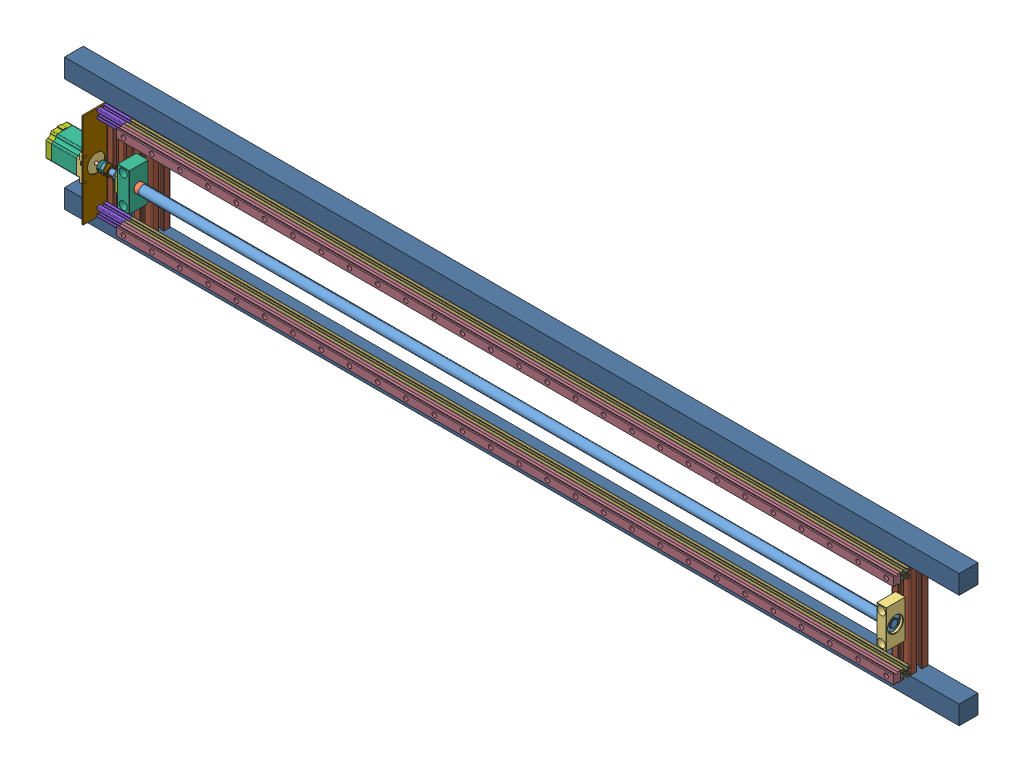
SolidWorks assembly Linke_seite, configuration Standard. Lengths in mm.
Overall size (1900 280 89.2).
42 component instances, 28 part files, 47 mates.
Components (placement in the parent):
- y.1-1: y.1 [Standard] at (-1768.993 -964.2695 1185.6748) x (-1 0 0) z (0 -0.561643 0.82738) size (1670 20 20)
- y.3-1: y.3 [Standard] at (-1768.993 -964.2695 1185.6748) x (-1 0 0) z (0 0.924225 0.381849) size (15 20 20)
- buv15_2_14b-1: buv15_2_14b [Standard] at (-1786.493 -964.2695 1185.6748) x (1 0 0) z (0 -1 0) size (20 41 80)
  - y.1.1.1-1: y.1.1.1 [Standard] at origin size (20 41 80)
  - y.2.1.1-1: y.2.1.1 [Standard] at (5 0 0) size (1 20 17.6)
  - y.3.1.1-1: y.3.1.1 [Standard] at origin size (9 32 32)
- bsv15_2_14b-1: bsv15_2_14b [Standard] at (-3373.993 -964.2695 1185.6748) x (-1 0 0) z (0 1 0) size (43 41 80)
  - y.1.1-1: y.1.1 [Standard] at origin size (25 41 80)
  - y.2.1-1: y.2.1 [Standard] at origin size (8 37 37)
  - y.3.1-1: y.3.1 [Standard] at origin size (18 32 32)
  - y.4.1-1: y.4.1 [Standard] at origin size (10 20 20)
  - y.5.1-1: y.5.1 [Standard] at origin size (10 26.45 26.45)
- bosch_3842993120_6do5v09iy6ebk03fg871s10o3-1: bosch_3842993120_6do5v09iy6ebk03fg871s10o3 [Default] at (-1776.493 -1064.2695 1144.6748) x (0 1 0) z (0 0 1) size (200 40 40)
- bosch_3842993120_6do5v09iy6ebk03fg871s10o3-2: bosch_3842993120_6do5v09iy6ebk03fg871s10o3 [Default] at (-3386.493 -1064.2695 1144.6748) x (0 1 0) z (0 0 1) size (200 40 40)
- bosch_3842992888_e3htx9vi1mc72io2jozt5vwey-1: bosch_3842992888_e3htx9vi1mc72io2jozt5vwey [Default] at (-3406.493 -874.2695 1174.6748) size (1650 20 20)
- bosch_3842992888_e3htx9vi1mc72io2jozt5vwey-2: bosch_3842992888_e3htx9vi1mc72io2jozt5vwey [Default] at (-3406.493 -1054.2695 1174.6748) size (1650 20 20)
- y.1.1.1.1-1: y.1.1.1.1 [Standard] at (-2581.493 -1054.2695 1184.6748) x (0 1 0) z (1 0 0) size (20 15.5 1650)
- y.1.1.1.1-2: y.1.1.1.1 [Standard] at (-2581.493 -874.2695 1184.6748) x (0 -1 0) z (-1 0 0) size (20 15.5 1650)
- mco20_6_35_10_2_14b-1: mco20_6_35_10_2_14b [Standard] at (-3442.293 -964.2695 1185.6748) size (21.4 21 21)
  - y.a-1: y.a [Standard] at origin size (6.6 21 21)
  - y.b-1: y.b [Standard] at origin size (10.2 20 20)
  - y.c-1: y.c [Standard] at origin size (4 4 5.1)
  - y.d-1: y.d [Standard] at origin size (4 5.1 4)
  - y.e-1: y.e [Standard] at origin size (10.2 20 20)
  - y.f-1: y.f [Standard] at origin size (4 5.1 4)
  - y.g-1: y.g [Standard] at origin size (4 4 5.1)
- ST5918L1008-1: ST5918L1008 [Standard] at (-3470.893 -964.2695 1185.6748) x (0 0 -1) z (1 0 0) size (56.4 58.1 96.6)
  - Frontcap_ST5918-1: Frontcap_ST5918 [Standard] at (0 0 -6.3) size (56.4 56.4 12.6)
  - shaft_forward_5709-1: shaft_forward_5709 [Standard] at (0 0 25.3) x (1 0 0) z (0 0 -1) size (6.35 6.35 19)
  - Schrauben_ISO_7045_M3-1: Schrauben_ISO_7045_M3 [Standard] at (-11.2 -25.35 2.2) x (0 1 0) z (1 0 0) size (5.57 2.46 5.76)
  - Schrauben_ISO_7045_M3-2: Schrauben_ISO_7045_M3 [Standard] at (25.35 -11.2 2.2) x (1 0 0) z (0 -1 0) size (5.57 2.46 5.76)
  - Schrauben_ISO_7045_M3-3: Schrauben_ISO_7045_M3 [Standard] at (11.2 25.35 2.2) x (1 0 0) z (0 -1 0) size (5.57 2.46 5.76)
  - Schrauben_ISO_7045_M3-4: Schrauben_ISO_7045_M3 [Standard] at (-25.35 11.2 2.2) x (1 0 0) z (0 -1 0) size (5.57 2.46 5.76)
  - Stator_5918_L-1: Stator_5918_L [Standard] at (0 0 -6.3) x (1 0 0) z (0 0 -1) size (56.4 56.4 53)
  - Endcap ST5918_kompl-1: Endcap ST5918_kompl [Standard] at (0 0.85 -65.3) x (1 0 0) z (0 0 -1) size (56.4 58.1 12)
    - Endcap_5918-1: Endcap_5918 [Standard] at (0 0.85 -6) size (56.4 58.1 12)
- bosch_3842992888_aff6iaz91xwbgzhnykkapvmd0-1: bosch_3842992888_aff6iaz91xwbgzhnykkapvmd0 [Default] at (-3463.193 -1054.2695 1174.6748) size (54.7 20 20)
- bosch_3842992888_aff6iaz91xwbgzhnykkapvmd0-2: bosch_3842992888_aff6iaz91xwbgzhnykkapvmd0 [Default] at (-3463.193 -874.2695 1174.6748) size (54.7 20 20)
- bosch_3842993120_6do5v09iy6ebk03fg871s10o3-3: bosch_3842993120_6do5v09iy6ebk03fg871s10o3 [Default] at (-3443.193 -1064.2695 1144.6748) x (0 1 0) z (0 0 1) size (200 40 40)
- Motorplatte_y.Achse-1: Motorplatte_y.Achse [Standard] at (-3463.193 -1064.2695 1124.6748) x (0 1 0) z (1 0 0) size (200 89.2 3)
- bosch_3842993120_2dhdbkbtd5fyfxp6933e5ukc1-1: bosch_3842993120_2dhdbkbtd5fyfxp6933e5ukc1 [Default] at (-1652.193 -844.2695 1144.6748) x (-1 0 0) z (0 -1 0) size (1900 40 40)
- bosch_3842993120_2dhdbkbtd5fyfxp6933e5ukc1-2: bosch_3842993120_2dhdbkbtd5fyfxp6933e5ukc1 [Default] at (-3552.193 -1084.2695 1144.6748) size (1900 40 40)
Mates (geometry in assembly coordinates):
- Konzentrisch1: concentric aligned: cylinder of y.1-1 through (-3391.393 -964.2695 1185.6748) axis (-1 0 0) radius 7.5; cylinder of y.3-1 through (-3371.493 -964.2695 1185.6748) axis (-1 0 0) radius 7.5
- Deckungsgleich1: coincident anti-aligned: plane of y.1-1 through (-3363.993 -971.6332 1180.6762) normal (-1 0 0); plane of y.3-1 through (-3363.993 -967.668 1193.9004) normal (1 0 0)
- Konzentrisch3: concentric aligned: cylinder of y.1-1 through (-1776.343 -964.2695 1185.6748) axis (-1 0 0) radius 7.5; cylinder of buv15_2_14b-1/y.3.1.1-1 through (-1776.493 -964.2695 1185.6748) axis (-1 0 0) radius 7.5
- Deckungsgleich3: coincident anti-aligned: plane of y.1-1 through (-1780.993 -971.4264 1180.8166) normal (1 0 0); plane of buv15_2_14b-1/y.3.1.1-1 through (-1780.993 -964.2695 1176.9498) normal (-1 0 0)
- Deckungsgleich4: coincident anti-aligned: plane of y.3-1 through (-3378.993 -967.668 1193.9004) normal (-1 0 0); plane of bsv15_2_14b-1/y.3.1-1 through (-3378.993 -964.2695 1177.0998) normal (1 0 0)
- Konzentrisch4: concentric anti-aligned: cylinder of y.1-1 through (-3391.393 -964.2695 1185.6748) axis (-1 0 0) radius 7.5; cylinder of bsv15_2_14b-1/y.3.1-1 through (-3383.418 -964.2695 1185.6748) axis (1 0 0) radius 7.5
- Deckungsgleich5: coincident aligned: plane of buv15_2_14b-1/y.1.1.1-1 through (-1766.993 -1004.2695 1205.6748) normal (0 0 1); plane of bsv15_2_14b-1/y.1.1-1 through (-3398.493 -924.2695 1205.6748) normal (0 0 1)
- Abstand2: distance = 60 mm aligned: plane of buv15_2_14b-1/y.1.1.1-1 through (-1786.493 -924.2695 1185.6748) normal (0 1 0); plane of bosch_3842993120_6do5v09iy6ebk03fg871s10o3-1 through (-1776.493 -864.2695 1144.6748) normal (0 1 0)
- Deckungsgleich8: coincident anti-aligned: plane of buv15_2_14b-1/y.1.1.1-1 through (-1785.993 -1004.2695 1164.6748) normal (0 0 -1); plane of bosch_3842993120_6do5v09iy6ebk03fg871s10o3-1 through (-1782.293 -1064.2695 1164.6748) normal (0 0 1)
- Abstand1: distance = 10 mm aligned: plane of bosch_3842993120_6do5v09iy6ebk03fg871s10o3-1 through (-1796.493 -1064.2695 1161.6748) normal (-1 0 0); plane of buv15_2_14b-1/y.1.1.1-1 through (-1786.493 -1004.2695 1205.1748) normal (-1 0 0)
- Deckungsgleich10: coincident anti-aligned: plane of bsv15_2_14b-1/y.1.1-1 through (-3374.493 -924.2695 1164.6748) normal (0 0 -1); plane of bosch_3842993120_6do5v09iy6ebk03fg871s10o3-2 through (-3369.493 -1064.2695 1164.6748) normal (0 0 1)
- Abstand3: distance = 60 mm aligned: plane of bosch_3842993120_6do5v09iy6ebk03fg871s10o3-2 through (-3386.493 -864.2695 1144.6748) normal (0 1 0); plane of bsv15_2_14b-1/y.1.1-1 through (-3373.993 -924.2695 1185.6748) normal (0 1 0)
- Abstand4: distance = 7.5 mm aligned: plane of bosch_3842993120_6do5v09iy6ebk03fg871s10o3-2 through (-3406.493 -1064.2695 1161.6748) normal (-1 0 0); plane of bsv15_2_14b-1/y.1.1-1 through (-3398.993 -924.2695 1165.1748) normal (-1 0 0)
- Deckungsgleich11: coincident aligned: plane of bosch_3842993120_6do5v09iy6ebk03fg871s10o3-2 through (-3406.493 -1064.2695 1161.6748) normal (-1 0 0); plane of bosch_3842992888_e3htx9vi1mc72io2jozt5vwey-1 through (-3406.493 -874.2695 1174.6748) normal (-1 0 0)
- Deckungsgleich12: coincident aligned: plane of bosch_3842993120_6do5v09iy6ebk03fg871s10o3-2 through (-3386.493 -864.2695 1144.6748) normal (0 1 0); plane of bosch_3842992888_e3htx9vi1mc72io2jozt5vwey-1 through (-3406.493 -864.2695 1183.1748) normal (0 1 0)
- Deckungsgleich13: coincident anti-aligned: plane of bosch_3842993120_6do5v09iy6ebk03fg871s10o3-2 through (-3369.493 -1064.2695 1164.6748) normal (0 0 1); plane of bosch_3842992888_e3htx9vi1mc72io2jozt5vwey-1 through (-3406.493 -865.7695 1164.6748) normal (0 0 -1)
- Deckungsgleich14: coincident aligned: plane of bosch_3842993120_6do5v09iy6ebk03fg871s10o3-1 through (-1756.493 -1064.2695 1150.4748) normal (1 0 0); plane of bosch_3842992888_e3htx9vi1mc72io2jozt5vwey-2 through (-1756.493 -1054.2695 1174.6748) normal (1 0 0)
- Deckungsgleich15: coincident aligned: plane of bosch_3842993120_6do5v09iy6ebk03fg871s10o3-1 through (-1776.493 -1064.2695 1144.6748) normal (0 -1 0); plane of bosch_3842992888_e3htx9vi1mc72io2jozt5vwey-2 through (-3406.493 -1064.2695 1178.1748) normal (0 -1 0)
- Deckungsgleich16: coincident anti-aligned: plane of bosch_3842993120_6do5v09iy6ebk03fg871s10o3-1 through (-1759.493 -1064.2695 1164.6748) normal (0 0 1); plane of bosch_3842992888_e3htx9vi1mc72io2jozt5vwey-2 through (-3406.493 -1057.7695 1164.6748) normal (0 0 -1)
- Deckungsgleich18: coincident anti-aligned: plane of bosch_3842992888_e3htx9vi1mc72io2jozt5vwey-2 through (-3406.493 -1050.7695 1184.6748) normal (0 0 1); plane of y.1.1.1.1-1 through (-1756.493 -1064.2695 1184.6748) normal (0 0 -1)
- Deckungsgleich19: coincident aligned: plane of bosch_3842992888_e3htx9vi1mc72io2jozt5vwey-2 through (-1756.493 -1054.2695 1174.6748) normal (1 0 0); plane of y.1.1.1.1-1 through (-1756.493 -1054.2695 1184.6748) normal (1 0 0)
- Deckungsgleich20: coincident aligned: plane of bosch_3842992888_e3htx9vi1mc72io2jozt5vwey-2 through (-3406.493 -1064.2695 1178.1748) normal (0 -1 0); plane of y.1.1.1.1-1 through (-1756.493 -1064.2695 1190.8548) normal (0 -1 0)
- Deckungsgleich21: coincident anti-aligned: plane of bosch_3842992888_e3htx9vi1mc72io2jozt5vwey-1 through (-3406.493 -870.7695 1184.6748) normal (0 0 1); plane of y.1.1.1.1-2 through (-3406.493 -864.2695 1184.6748) normal (0 0 -1)
- Deckungsgleich22: coincident aligned: plane of bosch_3842992888_e3htx9vi1mc72io2jozt5vwey-1 through (-3406.493 -874.2695 1174.6748) normal (-1 0 0); plane of y.1.1.1.1-2 through (-3406.493 -874.2695 1184.6748) normal (-1 0 0)
- Deckungsgleich23: coincident aligned: plane of bosch_3842992888_e3htx9vi1mc72io2jozt5vwey-1 through (-3406.493 -884.2695 1178.1748) normal (0 -1 0); plane of y.1.1.1.1-2 through (-3406.493 -884.2695 1184.6748) normal (0 -1 0)
- Konzentrisch6: concentric aligned: cylinder of y.1-1 through (-3428.743 -964.2695 1185.6748) axis (-1 0 0) radius 6; cylinder of mco20_6_35_10_2_14b-1/y.e-1 through (-3436.693 -964.2695 1185.6748) axis (-1 0 0) radius 5
- Deckungsgleich40: coincident anti-aligned: plane of y.1-1 through (-3438.993 -966.5448 1184.1303) normal (-1 0 0); plane of mco20_6_35_10_2_14b-1/y.a-1 through (-3438.993 -964.2695 1178.3748) normal (1 0 0)
- Konzentrisch7: concentric anti-aligned: cylinder of mco20_6_35_10_2_14b-1/y.b-1 through (-3447.893 -964.2695 1185.6748) axis (1 0 0) radius 3.175; cylinder of ST5918L1008-1/shaft_forward_5709-1 through (-3445.593 -964.2695 1185.6748) axis (-1 0 0) radius 3.175
- Deckungsgleich42: coincident anti-aligned: plane of mco20_6_35_10_2_14b-1/y.a-1 through (-3445.593 -964.2695 1178.3748) normal (-1 0 0); plane of ST5918L1008-1/shaft_forward_5709-1 through (-3445.593 -964.2695 1185.6748) normal (1 0 0)
- Deckungsgleich43: coincident: plane of bosch_3842992888_e3htx9vi1mc72io2jozt5vwey-2 through (-3406.493 -1054.2695 1174.6748) normal (-1 0 0); plane of bosch_3842992888_aff6iaz91xwbgzhnykkapvmd0-1 through (-3406.493 -1054.2695 1174.6748) normal (1 0 0)
- Deckungsgleich44: coincident aligned: plane of bosch_3842992888_e3htx9vi1mc72io2jozt5vwey-2 through (-3406.493 -1064.2695 1178.1748) normal (0 -1 0); plane of bosch_3842992888_aff6iaz91xwbgzhnykkapvmd0-1 through (-3463.193 -1064.2695 1178.1748) normal (0 -1 0)
- Deckungsgleich45: coincident aligned: plane of bosch_3842992888_e3htx9vi1mc72io2jozt5vwey-2 through (-3406.493 -1057.7695 1164.6748) normal (0 0 -1); plane of bosch_3842992888_aff6iaz91xwbgzhnykkapvmd0-1 through (-3463.193 -1057.7695 1164.6748) normal (0 0 -1)
- Deckungsgleich46: coincident: plane of bosch_3842992888_e3htx9vi1mc72io2jozt5vwey-1 through (-3406.493 -874.2695 1174.6748) normal (-1 0 0); plane of bosch_3842992888_aff6iaz91xwbgzhnykkapvmd0-2 through (-3406.493 -874.2695 1174.6748) normal (1 0 0)
- Deckungsgleich47: coincident aligned: plane of bosch_3842992888_e3htx9vi1mc72io2jozt5vwey-1 through (-3406.493 -864.2695 1183.1748) normal (0 1 0); plane of bosch_3842992888_aff6iaz91xwbgzhnykkapvmd0-2 through (-3463.193 -864.2695 1183.1748) normal (0 1 0)
- Deckungsgleich48: coincident aligned: plane of bosch_3842992888_e3htx9vi1mc72io2jozt5vwey-1 through (-3406.493 -865.7695 1164.6748) normal (0 0 -1); plane of bosch_3842992888_aff6iaz91xwbgzhnykkapvmd0-2 through (-3463.193 -865.7695 1164.6748) normal (0 0 -1)
- Deckungsgleich49: coincident aligned: plane of bosch_3842992888_aff6iaz91xwbgzhnykkapvmd0-1 through (-3463.193 -1064.2695 1166.1748) normal (0 -1 0); plane of bosch_3842993120_6do5v09iy6ebk03fg871s10o3-3 through (-3443.193 -1064.2695 1144.6748) normal (0 -1 0)
- Deckungsgleich50: coincident aligned: plane of bosch_3842992888_aff6iaz91xwbgzhnykkapvmd0-1 through (-3463.193 -1054.2695 1174.6748) normal (-1 0 0); plane of bosch_3842993120_6do5v09iy6ebk03fg871s10o3-3 through (-3463.193 -1064.2695 1161.6748) normal (-1 0 0)
- Deckungsgleich51: coincident anti-aligned: plane of bosch_3842992888_aff6iaz91xwbgzhnykkapvmd0-1 through (-3463.193 -1057.7695 1164.6748) normal (0 0 -1); plane of bosch_3842993120_6do5v09iy6ebk03fg871s10o3-3 through (-3448.993 -1064.2695 1164.6748) normal (0 0 1)
- Deckungsgleich52: coincident aligned: plane of bosch_3842993120_6do5v09iy6ebk03fg871s10o3-3 through (-3460.193 -1064.2695 1124.6748) normal (0 0 -1); plane of Motorplatte_y.Achse-1 through (-3466.193 -1064.2695 1124.6748) normal (0 0 -1)
- Deckungsgleich53: coincident aligned: plane of bosch_3842992888_aff6iaz91xwbgzhnykkapvmd0-1 through (-3463.193 -1064.2695 1166.1748) normal (0 -1 0); plane of Motorplatte_y.Achse-1 through (-3466.193 -1064.2695 1124.6748) normal (0 -1 0)
- Deckungsgleich54: coincident anti-aligned: plane of bosch_3842993120_6do5v09iy6ebk03fg871s10o3-3 through (-3463.193 -1064.2695 1138.8748) normal (-1 0 0); plane of Motorplatte_y.Achse-1 through (-3463.193 -1064.2695 1124.6748) normal (1 0 0)
- Deckungsgleich55: coincident anti-aligned: plane of bosch_3842993120_6do5v09iy6ebk03fg871s10o3-2 through (-3386.493 -864.2695 1144.6748) normal (0 1 0); plane of bosch_3842993120_2dhdbkbtd5fyfxp6933e5ukc1-1 through (-2602.193 -864.2695 1144.6748) normal (0 -1 0)
- Deckungsgleich56: coincident aligned: plane of bosch_3842993120_6do5v09iy6ebk03fg871s10o3-3 through (-3437.393 -1064.2695 1124.6748) normal (0 0 -1); plane of bosch_3842993120_2dhdbkbtd5fyfxp6933e5ukc1-1 through (-2602.193 -844.2695 1124.6748) normal (0 0 -1)
- Abstand5: distance = 86 mm aligned: plane of bosch_3842993120_2dhdbkbtd5fyfxp6933e5ukc1-1 through (-3552.193 -844.2695 1144.6748) normal (-1 0 0); plane of Motorplatte_y.Achse-1 through (-3466.193 -1064.2695 1124.6748) normal (-1 0 0)
- Abstand6: distance = 86 mm aligned: plane of bosch_3842993120_2dhdbkbtd5fyfxp6933e5ukc1-2 through (-3552.193 -1084.2695 1144.6748) normal (-1 0 0); plane of Motorplatte_y.Achse-1 through (-3466.193 -1064.2695 1124.6748) normal (-1 0 0)
- Deckungsgleich60: coincident aligned: plane of bosch_3842993120_6do5v09iy6ebk03fg871s10o3-2 through (-3380.693 -1064.2695 1124.6748) normal (0 0 -1); plane of bosch_3842993120_2dhdbkbtd5fyfxp6933e5ukc1-2 through (-2602.193 -1084.2695 1124.6748) normal (0 0 -1)
- Deckungsgleich61: coincident anti-aligned: plane of bosch_3842993120_6do5v09iy6ebk03fg871s10o3-2 through (-3386.493 -1064.2695 1144.6748) normal (0 -1 0); plane of bosch_3842993120_2dhdbkbtd5fyfxp6933e5ukc1-2 through (-2602.193 -1064.2695 1144.6748) normal (0 1 0)
